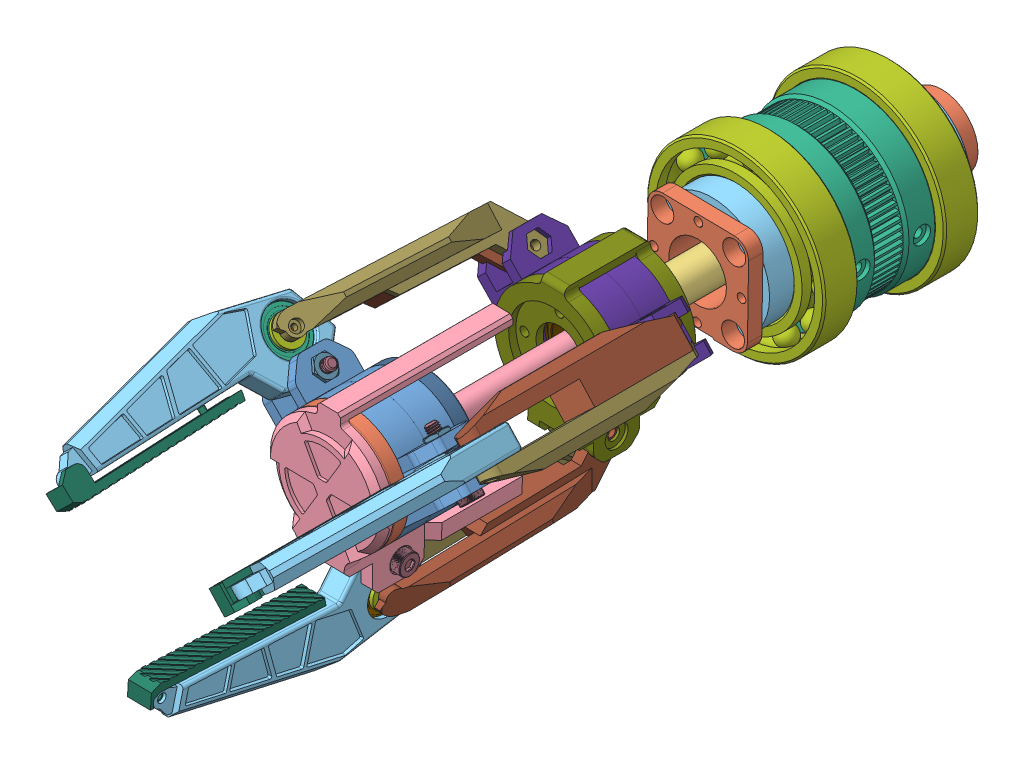
SolidWorks assembly CrawAssemV2, configuration EX2. Lengths in mm.
Overall size (95.83 96.83 278.95).
52 component instances, 26 part files, 110 mates.
Components (placement in the parent):
- CrawPivotL-1: CrawPivotL [Default] at (23.6534 28.2906 36.4169) x (0.675201 -0.737634 0) z (0 0 1)
- RotorInner-1: RotorInner [Default] at (23.6534 28.2906 51.4169) x (-0.675201 0.737634 0) z (0 0 -1)
- 4668K131_Permanently Lubricated Stainless Steel Ball Bearing-1: 4668K131_Permanently Lubricated Stainless Steel Ball Bearing [4668K131] at (23.6534 28.2906 52.4169) x (0.977927 0.208948 0) z (0 0 1)
- RotorOutter-1: RotorOutter [Default] at (23.6534 28.2906 56.4169) x (-0.999871 0.016078 0) z (0 0 -1)
- CrawPivotL-2: CrawPivotL [Default] at (23.6534 28.2906 36.4169) x (-0.716673 -0.697409 0) z (0 0 -1)
- FrontCraw-1: FrontCraw [Default] at (-7.9204 40.6623 113.525) x (-0.024761 0.025445 -0.99937) z (0.69697 -0.716221 -0.035504)
- FrontCraw-2: FrontCraw [Default] at (49.7643 43.7862 113.4714) x (0.035168 0.032192 -0.998863) z (-0.736795 -0.674433 -0.047677)
- 4668K334_Permanently Lubricated Stainless Steel Ball Bearing-1: 4668K334_Permanently Lubricated Stainless Steel Ball Bearing [4668K334] at (58.2277 46.2461 36.989) x (0.461728 0.422648 0.779857) z (-0.675201 0.737634 0)
- BearingStop1-1: BearingStop1 [Default] at (56.5397 48.0902 36.989) x (-0.727461 -0.665889 0.165503) z (0.675201 -0.737634 0)
- 4668K334_Permanently Lubricated Stainless Steel Ball Bearing-2: 4668K334_Permanently Lubricated Stainless Steel Ball Bearing [4668K334] at (-9.9873 48.3784 36.952) x (0.471273 -0.484291 0.737132) z (-0.716673 -0.697409 0)
- BearingStop1-2: BearingStop1 [Default] at (-11.779 46.6349 36.952) x (-0.683695 0.702579 -0.197341) z (0.716673 0.697409 0)
- BearingStop2-1: BearingStop2 [Default] at (55.6957 49.0123 36.989) x (-0.727461 -0.665889 0.165503) z (0.675201 -0.737634 0)
- BearingStop2-2: BearingStop2 [Default] at (-12.6749 45.7632 36.952) x (-0.683695 0.702579 -0.197341) z (0.716673 0.697409 0)
- FrontCraw-3: FrontCraw [Default] at (27.1452 -3.3521 113.4714) x (-0.000767 -0.047671 -0.998863) z (0.016059 0.998734 -0.047677)
- 7804K117_Stainless Steel Ball Bearing-1: 7804K117_Stainless Steel Ball Bearing [7804K117] at (23.1186 -11.1922 36.989) x (-0.007051 -0.438494 -0.898707) z (0.999871 -0.016078 0)
- BearingStop2-3: BearingStop2 [Default] at (19.3691 -11.1319 36.989) x (0.016038 0.997394 0.070343) z (0.999871 -0.016078 0)
- BearingStop1-3: BearingStop1 [Default] at (20.6189 -11.152 36.989) x (0.016038 0.997394 0.070343) z (0.999871 -0.016078 0)
- RotorInnerBack-1: RotorInnerBack [Default] at (23.6534 28.2906 21.4169) x (0.962311 -0.271952 0) z (0 0 1)
- SEC2pull1-1: SEC2pull1 [Default] at (-10.6231 40.787 37.118) x (0.023165 -0.023805 -0.999448) z (0.716673 0.697409 0)
- SEC2pull2-1: SEC2pull2 [Default] at (-3.4564 47.7611 37.118) x (0.023165 -0.023805 -0.999448) z (0.716673 0.697409 0)
- 91290A164_Black-Oxide Alloy Steel Socket Head Screw-1: 91290A164_Black-Oxide Alloy Steel Socket Head Screw [91290A164] at (23.2113 0.7942 36.4169) x (0.000258 0.016076 -0.999871) z (0.999871 -0.016078 0)
- 90592A090_Steel Hex Nut (1)-1: 90592A090_Steel Hex Nut (1) [90592A090] at (14.6124 0.9324 36.4169) x (0.016078 0.999871 0) z (0 0 1)
- 91290A164_Black-Oxide Alloy Steel Socket Head Screw-2: 91290A164_Black-Oxide Alloy Steel Socket Head Screw [91290A164] at (-0.6785 40.3897 36.4169) x (-0.0003 0.000308 -1) z (-0.716673 -0.697409 0)
- 90592A090_Steel Hex Nut (1)-2: 90592A090_Steel Hex Nut (1) [90592A090] at (4.0516 44.9926 36.4169) x (-0.348705 0.358336 -0.866025) z (-0.603974 0.620657 0.5)
- 91290A164_Black-Oxide Alloy Steel Socket Head Screw-3: 91290A164_Black-Oxide Alloy Steel Socket Head Screw [91290A164] at (48.6435 38.9643 36.4169) x (-0.209995 -0.192222 0.95862) z (0.675201 -0.737634 0)
- 90592A090_Steel Hex Nut (1)-3: 90592A090_Steel Hex Nut (1) [90592A090] at (44.1872 43.8327 36.4169) x (-0.368817 -0.3376 -0.866025) z (-0.63881 -0.584741 0.5)
- UpperSecCraw (1)-1: UpperSecCraw (1) [Default] at (-7.216 44.2401 113.6369) x (-0.024761 0.025445 -0.99937) z (0.716673 0.697409 0)
- UpperSecCraw (1)-2: UpperSecCraw (1) [Default] at (24.1122 -5.3749 113.6086) x (-0.000767 -0.047671 -0.998863) z (-0.999871 0.016078 0)
- UpperSecCraw (1)-3: UpperSecCraw (1) [Default] at (53.3178 42.9719 113.6086) x (0.035168 0.032192 -0.998863) z (0.675201 -0.737634 0)
- RTL-1: RTL [Default] at (23.6534 28.2906 -18.4955) x (-0.999871 0.016078 0) z (0 0 -1)
- PullPivot-1: PullPivot [Default] at (23.6534 28.2906 -38.4955) x (0.675201 -0.737634 0) z (0 0 1)
- 5972K213_Ball Bearing-1: 5972K213_Ball Bearing [5972K213] at (23.6534 28.2906 -33.4955)
- PullPivot2-1: PullPivot2 [Default] at (23.6534 28.2906 -38.4955) x (0.999025 -0.044147 0) z (0 0 1)
- PullPivot-2: PullPivot [Default] at (23.6534 28.2906 -38.4955) x (-0.716673 -0.697409 0) z (0 0 -1)
- 5972K213_Ball Bearing-2: 5972K213_Ball Bearing [5972K213] at (23.6534 28.2906 -43.4955) x (0.923728 0.383049 0) z (0 0 -1)
- PullPivot2-2: PullPivot2 [Default] at (23.6534 28.2906 -38.4955) x (-0.716673 -0.697409 0) z (0 0 -1)
- SEC2pull1-4: SEC2pull1 [Default] at (50.6589 47.1131 37.1398) x (-0.022244 -0.020361 -0.999545) z (0.675201 -0.737634 0)
- SEC2pull1-5: SEC2pull1 [Default] at (29.1982 -6.2916 37.1398) x (0.000485 0.030152 -0.999545) z (-0.999871 0.016078 0)
- SEC2pull2-7: SEC2pull2 [Default] at (19.5494 -6.1365 37.1398) x (0.000485 0.030152 -0.999545) z (-0.999871 0.016078 0)
- SEC2pull2-8: SEC2pull2 [Default] at (57.4109 39.7367 37.1398) x (-0.022244 -0.020361 -0.999545) z (0.675201 -0.737634 0)
- CylinderTube-1: CylinderTube [Default] at (23.6534 28.2906 -74.2503) x (-0.999871 0.016078 0) z (-0.016078 -0.999871 0)
- Hydro2-2: Hydro2 [Default] at (23.6534 28.2906 -50.4955) x (-0.999871 0.016078 0) z (0 0 -1) size (30 30 73)
- 6112K44_Linear Motion Shaft-1: 6112K44_Linear Motion Shaft [6112K44] at (23.6534 28.2906 -52.5831) x (-0.201275 -0.979535 0) z (0 0 1) size (8 8 100)
- Cylinder40mmCover-1: Cylinder40mmCover [Default] at (23.6534 28.2906 -79.2503) x (-0.999871 0.016078 0) z (0 0 -1) size (40 40 70)
- PiV1-1: PiV1 [Default] at (23.6534 28.2906 -129.2503) x (0.999871 -0.016078 0) z (0 0 1) size (55 55 30)
- PiVEnclosure1-1: PiVEnclosure1 [Default] at (23.6534 28.2906 -109.2503) x (0.791208 -0.611547 0) z (0 0 1) size (75 75 13) (hidden)
- 4668K334_Permanently Lubricated Stainless Steel Ball Bearing-3: 4668K334_Permanently Lubricated Stainless Steel Ball Bearing [4668K334] at (19.2674 62.5359 -106.7503) (hidden)
- 4668K334_Permanently Lubricated Stainless Steel Ball Bearing-4: 4668K334_Permanently Lubricated Stainless Steel Ball Bearing [4668K334] at (-10.5918 23.9046 -106.7503) (hidden)
- 4668K334_Permanently Lubricated Stainless Steel Ball Bearing-5: 4668K334_Permanently Lubricated Stainless Steel Ball Bearing [4668K334] at (28.0395 -5.9546 -106.7503) (hidden)
- 4668K334_Permanently Lubricated Stainless Steel Ball Bearing-6: 4668K334_Permanently Lubricated Stainless Steel Ball Bearing [4668K334] at (57.8987 32.6767 -106.7503) (hidden)
- 5972K249_Ball Bearing-1: 5972K249_Ball Bearing [5972K249] at (23.6534 28.2906 -93.2503) x (0.88466 0.466238 0) z (0 0 1) size (62 62 12)
- 5972K249_Ball Bearing-2: 5972K249_Ball Bearing [5972K249] at (23.6534 28.2906 -135.2503) x (0.910111 -0.414364 0) z (0 0 1) size (62 62 12)
Mates (geometry in assembly coordinates):
- Concentric1: concentric aligned: cylinder of CrawPivotL-1 through (36.9309 40.4442 36.4169) axis (0 0 1) radius 1.3; cylinder of RotorInner-1 through (36.9309 40.4442 43.4169) axis (0 0 1) radius 1.15
- Concentric2: concentric aligned: circle of CrawPivotL-1; cylinder of RotorInner-1 through (40.8175 22.8689 43.4169) axis (0 0 1) radius 1.15
- Coincident2: coincident anti-aligned: plane of CrawPivotL-1 through (23.6534 28.2906 46.4169) normal (0 0 1); plane of RotorInner-1 through (23.6534 28.2906 46.4169) normal (0 0 -1)
- Concentric3: concentric anti-aligned: cylinder of RotorInner-1 through (23.6534 28.2906 54.9169) axis (0 0 -1) radius 3.85; cylinder of 4668K131_Permanently Lubricated Stainless Steel Ball Bearing-1 through (23.6534 28.2906 54.4169) axis (0 0 1) radius 4
- Coincident3: coincident anti-aligned: plane of RotorInner-1 through (23.6534 28.2906 50.4169) normal (0 0 1); plane of 4668K131_Permanently Lubricated Stainless Steel Ball Bearing-1 through (22.4926 33.7235 50.4169) normal (0 0 -1)
- Concentric4: concentric anti-aligned: cylinder of 4668K131_Permanently Lubricated Stainless Steel Ball Bearing-1 through (23.6534 28.2906 54.4169) axis (0 0 1) radius 8; cylinder of RotorOutter-1 through (23.6534 28.2906 54.4169) axis (0 0 -1) radius 8
- Coincident4: coincident anti-aligned: plane of 4668K131_Permanently Lubricated Stainless Steel Ball Bearing-1 through (22.0237 35.9184 54.4169) normal (0 0 1); plane of RotorOutter-1 through (23.6534 28.2906 54.4169) normal (0 0 -1)
- Coincident5: coincident anti-aligned: plane of CrawPivotL-1 through (23.6534 28.2906 36.4169) normal (0 0 -1); plane of CrawPivotL-2 through (23.6534 28.2906 36.4169) normal (0 0 1)
- Coincident6: coincident anti-aligned: circle of CrawPivotL-1; circle of CrawPivotL-2
- Concentric7: concentric anti-aligned: cylinder of FrontCraw-2 through (56.5397 48.0902 36.989) axis (0.675201 -0.737634 0) radius 8; cylinder of 4668K334_Permanently Lubricated Stainless Steel Ball Bearing-1 through (56.5397 48.0902 36.989) axis (-0.675201 0.737634 0) radius 8
- Coincident10: coincident anti-aligned: plane of FrontCraw-2 through (56.5397 48.0902 36.989) normal (0.675201 -0.737634 0); plane of 4668K334_Permanently Lubricated Stainless Steel Ball Bearing-1 through (60.9979 52.1711 32.1378) normal (-0.675201 0.737634 0)
- Concentric8: concentric aligned: cylinder of 4668K334_Permanently Lubricated Stainless Steel Ball Bearing-1 through (56.5397 48.0902 36.989) axis (-0.675201 0.737634 0) radius 4; cylinder of BearingStop1-1 through (59.9157 44.4021 36.989) axis (-0.675201 0.737634 0) radius 3.9
- Coincident11: coincident anti-aligned: plane of 4668K334_Permanently Lubricated Stainless Steel Ball Bearing-1 through (63.0477 47.2689 33.581) normal (0.675201 -0.737634 0); plane of BearingStop1-1 through (59.9157 44.4021 36.989) normal (-0.675201 0.737634 0)
- Concentric9: concentric anti-aligned: cylinder of FrontCraw-1 through (-11.779 46.6349 36.952) axis (0.716673 0.697409 0) radius 8; cylinder of 4668K334_Permanently Lubricated Stainless Steel Ball Bearing-2 through (-11.779 46.6349 36.952) axis (-0.716673 -0.697409 0) radius 8
- Coincident12: coincident anti-aligned: plane of FrontCraw-1 through (-11.779 46.6349 36.952) normal (0.716673 0.697409 0); plane of 4668K334_Permanently Lubricated Stainless Steel Ball Bearing-2 through (-15.7632 50.7291 42.189) normal (-0.716673 -0.697409 0)
- Concentric11: concentric aligned: cylinder of 4668K334_Permanently Lubricated Stainless Steel Ball Bearing-2 through (-11.779 46.6349 36.952) axis (-0.716673 -0.697409 0) radius 4; cylinder of BearingStop1-2 through (-8.1957 50.122 36.952) axis (-0.716673 -0.697409 0) radius 3.9
- Coincident13: coincident anti-aligned: plane of 4668K334_Permanently Lubricated Stainless Steel Ball Bearing-2 through (-10.9946 52.9982 40.631) normal (0.716673 0.697409 0); plane of BearingStop1-2 through (-8.1957 50.122 36.952) normal (-0.716673 -0.697409 0)
- Concentric12: concentric aligned: cylinder of BearingStop1-1 through (60.7598 43.48 36.989) axis (-0.675201 0.737634 0) radius 3.05; cylinder of BearingStop2-1 through (60.591 43.6644 36.989) axis (-0.675201 0.737634 0) radius 2.95
- Coincident15: coincident anti-aligned: circle of BearingStop1-1; plane of BearingStop2-1 through (56.5397 48.0902 36.989) normal (0.675201 -0.737634 0)
- Concentric13: concentric aligned: cylinder of BearingStop1-2 through (-7.2998 50.9937 36.952) axis (-0.716673 -0.697409 0) radius 3.05; cylinder of BearingStop2-2 through (-7.479 50.8194 36.952) axis (-0.716673 -0.697409 0) radius 2.95
- Coincident17: coincident anti-aligned: plane of BearingStop1-2 through (-11.779 46.6349 36.952) normal (-0.716673 -0.697409 0); plane of BearingStop2-2 through (-11.779 46.6349 36.952) normal (0.716673 0.697409 0)
- Concentric14: concentric aligned: circle of RotorOutter-1; circle of FrontCraw-3
- Coincident18: coincident anti-aligned: plane of RotorOutter-1 through (27.1465 -3.2696 56.4169) normal (-0.999871 0.016078 0); plane of FrontCraw-3 through (27.1452 -3.3521 113.4714) normal (0.999871 -0.016078 0)
- Concentric15: concentric anti-aligned: cylinder of FrontCraw-3 through (25.6183 -11.2324 36.989) axis (-0.999871 0.016078 0) radius 8; cylinder of 7804K117_Stainless Steel Ball Bearing-1 through (25.6183 -11.2324 36.989) axis (0.999871 -0.016078 0) radius 8
- Coincident20: coincident anti-aligned: plane of FrontCraw-3 through (25.6183 -11.2324 36.989) normal (-0.999871 0.016078 0); plane of 7804K117_Stainless Steel Ball Bearing-1 through (25.698 -6.2754 34.5697) normal (0.999871 -0.016078 0)
- Concentric16: concentric anti-aligned: cylinder of 7804K117_Stainless Steel Ball Bearing-1 through (25.6183 -11.2324 36.989) axis (0.999871 -0.016078 0) radius 4; cylinder of BearingStop1-3 through (25.6183 -11.2324 36.989) axis (-0.999871 0.016078 0) radius 3.9
- Coincident21: coincident anti-aligned: plane of 7804K117_Stainless Steel Ball Bearing-1 through (25.698 -6.2754 34.5697) normal (0.999871 -0.016078 0); plane of BearingStop1-3 through (25.6183 -11.2324 36.989) normal (-0.999871 0.016078 0)
- Concentric17: concentric aligned: cylinder of BearingStop2-3 through (26.6181 -11.2485 36.989) axis (-0.999871 0.016078 0) radius 2.95; cylinder of BearingStop1-3 through (26.8681 -11.2525 36.989) axis (-0.999871 0.016078 0) radius 3.05
- Coincident23: coincident anti-aligned: plane of 7804K117_Stainless Steel Ball Bearing-1 through (20.6803 -7.333 35.1252) normal (-0.999871 0.016078 0); plane of BearingStop2-3 through (20.6189 -11.152 36.989) normal (0.999871 -0.016078 0)
- Concentric18: concentric aligned: cylinder of CrawPivotL-2 through (28.5486 45.6122 36.4169) axis (0 0 -1) radius 1.3; cylinder of RotorInnerBack-1 through (28.5486 45.6122 29.4169) axis (0 0 -1) radius 0.725
- Concentric19: concentric aligned: cylinder of CrawPivotL-2 through (11.1001 41.1907 36.4169) axis (0 0 -1) radius 1.3; cylinder of RotorInnerBack-1 through (11.1001 41.1907 29.4169) axis (0 0 -1) radius 0.725
- Coincident24: coincident anti-aligned: plane of CrawPivotL-2 through (23.6534 28.2906 26.4169) normal (0 0 -1); plane of RotorInnerBack-1 through (23.6534 28.2906 26.4169) normal (0 0 1)
- Concentric26: concentric aligned: cylinder of BearingStop2-2 through (-7.479 50.8194 36.952) axis (-0.716673 -0.697409 0) radius 2.05; cylinder of SEC2pull1-1 through (-6.9415 51.3424 36.952) axis (-0.716673 -0.697409 0) radius 1.8
- Coincident28: coincident anti-aligned: plane of BearingStop2-2 through (-12.6749 45.7632 36.952) normal (-0.716673 -0.697409 0); plane of SEC2pull1-1 through (-12.6749 45.7632 36.952) normal (0.716673 0.697409 0)
- Coincident32: coincident anti-aligned: circle of SEC2pull1-1; circle of SEC2pull2-1
- Concentric29: concentric aligned: circle of SEC2pull1-1; cylinder of SEC2pull2-1 through (-8.0165 50.2963 36.952) axis (0.716673 0.697409 0) radius 1
- Concentric35: concentric anti-aligned: circle of RotorOutter-1; circle of 91290A164_Black-Oxide Alloy Steel Socket Head Screw-1
- Coincident38: coincident anti-aligned: plane of RotorOutter-1 through (30.2104 0.6816 36.4169) normal (0.999871 -0.016078 0); plane of 91290A164_Black-Oxide Alloy Steel Socket Head Screw-1 through (30.2096 0.6286 39.7164) normal (-0.999871 0.016078 0)
- Concentric36: concentric anti-aligned: circle of RotorOutter-1; circle of 90592A090_Steel Hex Nut (1)-1
- Coincident39: coincident anti-aligned: plane of RotorOutter-1 through (16.6544 28.4032 56.4169) normal (-0.999871 0.016078 0); plane of 90592A090_Steel Hex Nut (1)-1 through (16.1559 -2.5928 34.3961) normal (0.999871 -0.016078 0)
- Coincident40: coincident aligned: circle of CrawPivotL-2; circle of 91290A164_Black-Oxide Alloy Steel Socket Head Screw-2
- Coincident41: coincident aligned: circle of CrawPivotL-2; circle of 90592A090_Steel Hex Nut (1)-2
- Coincident42: coincident anti-aligned: plane of CrawPivotL-2 through (0.464 46.3851 34.3961) normal (0.697409 -0.716673 0); plane of 90592A090_Steel Hex Nut (1)-2 through (0.464 46.3851 38.4376) normal (-0.697409 0.716673 0)
- Coincident43: coincident anti-aligned: plane of RotorOutter-1 through (16.2685 4.4063 38.4376) normal (-0.016078 -0.999871 0); plane of 90592A090_Steel Hex Nut (1)-1 through (13.0689 4.4577 38.4376) normal (0.016078 0.999871 0)
- Coincident44: coincident anti-aligned: plane of CrawPivotL-2 through (-14.723 47.6528 46.4169) normal (0.716673 0.697409 0); plane of FrontCraw-1 through (-7.9204 40.6623 113.525) normal (-0.716673 -0.697409 0)
- Coincident45: coincident aligned: circle of CrawPivotL-1; circle of 91290A164_Black-Oxide Alloy Steel Socket Head Screw-3
- Coincident46: coincident aligned: circle of CrawPivotL-1; circle of 90592A090_Steel Hex Nut (1)-3
- Coincident47: coincident anti-aligned: plane of CrawPivotL-1 through (47.8492 45.0157 38.4376) normal (-0.737634 -0.675201 0); plane of 90592A090_Steel Hex Nut (1)-3 through (47.8492 45.0157 34.3961) normal (0.737634 0.675201 0)
- Concentric39: concentric anti-aligned: cylinder of FrontCraw-1 through (-9.366 42.1478 113.6369) axis (0.716673 0.697409 0) radius 2; cylinder of UpperSecCraw (1)-1 through (-5.066 46.3323 113.6369) axis (-0.716673 -0.697409 0) radius 1.975
- Coincident49: coincident anti-aligned: plane of FrontCraw-1 through (-9.8607 51.2595 115.1168) normal (0.716673 0.697409 0); plane of UpperSecCraw (1)-1 through (-5.066 46.3323 113.6369) normal (-0.716673 -0.697409 0)
- Parallel1: parallel anti-aligned: plane of FrontCraw-1 through (-2.1871 46.2416 113.525) normal (0.69697 -0.716221 -0.035504); plane of UpperSecCraw (1)-1 through (-5.987 44.411 68.9439) normal (-0.69697 0.716221 0.035504)
- Concentric40: concentric anti-aligned: cylinder of FrontCraw-3 through (27.1119 -5.4231 113.6086) axis (-0.999871 0.016078 0) radius 2; cylinder of UpperSecCraw (1)-2 through (21.1126 -5.3267 113.6086) axis (0.999871 -0.016078 0) radius 1.975
- Coincident52: coincident anti-aligned: plane of FrontCraw-3 through (21.0024 -12.1823 115.1721) normal (-0.999871 0.016078 0); plane of UpperSecCraw (1)-2 through (21.1126 -5.3267 113.6086) normal (0.999871 -0.016078 0)
- Parallel3: parallel anti-aligned: plane of FrontCraw-3 through (19.1462 -3.2235 113.4714) normal (0.016059 0.998734 -0.047677); plane of UpperSecCraw (1)-2 through (23.1154 -5.1688 68.91) normal (-0.016059 -0.998734 0.047677)
- Concentric41: concentric anti-aligned: cylinder of FrontCraw-2 through (51.2922 45.1848 113.6086) axis (0.675201 -0.737634 0) radius 2; cylinder of UpperSecCraw (1)-3 through (55.3434 40.759 113.6086) axis (-0.675201 0.737634 0) radius 1.975
- Coincident54: coincident anti-aligned: plane of FrontCraw-2 through (60.401 45.3885 115.1721) normal (0.675201 -0.737634 0); plane of UpperSecCraw (1)-3 through (55.3434 40.759 113.6086) normal (-0.675201 0.737634 0)
- Parallel4: parallel anti-aligned: plane of FrontCraw-2 through (55.1659 37.8852 113.4714) normal (-0.736795 -0.674433 -0.047677); plane of UpperSecCraw (1)-3 through (53.8528 42.1059 68.91) normal (0.736795 0.674433 0.047677)
- Coincident59: coincident anti-aligned: circle of RTL-1; circle of PullPivot-1
- Concentric49: concentric aligned: cylinder of PullPivot-1 through (23.6534 28.2906 -38.4955) axis (0 0 1) radius 12; cylinder of 5972K213_Ball Bearing-1 through (23.6534 28.2906 -30.9955) axis (0 0 1) radius 12
- Coincident61: coincident anti-aligned: plane of PullPivot-1 through (23.6534 28.2906 -30.9955) normal (0 0 -1); plane of 5972K213_Ball Bearing-1 through (23.6534 40.0406 -30.9955) normal (0 0 1)
- Coincident62: coincident anti-aligned: circle of PullPivot-1; circle of PullPivot2-1
- Concentric50: concentric aligned: cylinder of PullPivot-1 through (12.5889 18.1626 -28.4955) axis (0 0 -1) radius 2; cylinder of PullPivot2-1 through (12.5889 18.1626 -35.9955) axis (0 0 -1) radius 2
- Concentric52: concentric anti-aligned: circle of RotorInnerBack-1; circle of RTL-1
- Concentric53: concentric aligned: cylinder of PullPivot-2 through (23.6534 28.2906 -38.4955) axis (0 0 -1) radius 12; cylinder of 5972K213_Ball Bearing-2 through (23.6534 28.2906 -45.9955) axis (0 0 -1) radius 12
- Coincident65: coincident anti-aligned: plane of PullPivot-2 through (23.6534 28.2906 -45.9955) normal (0 0 1); plane of 5972K213_Ball Bearing-2 through (28.1543 17.4368 -45.9955) normal (0 0 -1)
- Coincident66: coincident anti-aligned: circle of PullPivot-2; circle of PullPivot2-2
- Concentric54: concentric aligned: cylinder of PullPivot-2 through (23.8578 43.2892 -48.4955) axis (0 0 1) radius 2; cylinder of PullPivot2-2 through (23.8578 43.2892 -40.9955) axis (0 0 1) radius 2
- Coincident67: coincident aligned: circle of RTL-1; circle of PullPivot-2
- Concentric56: concentric aligned: cylinder of BearingStop2-1 through (60.591 43.6644 36.989) axis (-0.675201 0.737634 0) radius 2.05; cylinder of SEC2pull1-4 through (61.0974 43.1112 36.989) axis (-0.675201 0.737634 0) radius 1.8
- Coincident68: coincident anti-aligned: plane of BearingStop2-1 through (55.6957 49.0123 36.989) normal (-0.675201 0.737634 0); plane of SEC2pull1-4 through (55.6957 49.0123 36.989) normal (0.675201 -0.737634 0)
- Coincident72: coincident anti-aligned: plane of SEC2pull1-4 through (61.0974 43.1112 36.989) normal (0.675201 -0.737634 0); plane of SEC2pull2-8 through (61.0974 43.1112 36.989) normal (-0.675201 0.737634 0)
- Concentric63: concentric anti-aligned: cylinder of SEC2pull1-4 through (44.491 43.5008 -38.4955) axis (0.675201 -0.737634 0) radius 1.5; cylinder of SEC2pull2-8 through (53.6062 33.5427 -38.4955) axis (-0.675201 0.737634 0) radius 1.5
- Concentric65: concentric anti-aligned: cylinder of BearingStop2-3 through (26.6181 -11.2485 36.989) axis (-0.999871 0.016078 0) radius 2.05; cylinder of SEC2pull1-5 through (19.1191 -11.1279 36.989) axis (0.999871 -0.016078 0) radius 1.8
- Coincident73: coincident anti-aligned: plane of BearingStop2-3 through (26.6181 -11.2485 36.989) normal (0.999871 -0.016078 0); plane of SEC2pull1-5 through (26.6181 -11.2485 36.989) normal (-0.999871 0.016078 0)
- Concentric66: concentric anti-aligned: cylinder of SEC2pull1-5 through (29.1178 -11.2887 36.989) axis (-0.999871 0.016078 0) radius 0.5; circle of SEC2pull2-7
- Coincident74: coincident anti-aligned: plane of BearingStop2-3 through (19.969 -11.1416 36.989) normal (-0.999871 0.016078 0); plane of SEC2pull2-7 through (19.969 -11.1416 36.989) normal (0.999871 -0.016078 0)
- Concentric67: concentric anti-aligned: cylinder of SEC2pull1-5 through (30.8103 0.672 -38.4955) axis (-0.999871 0.016078 0) radius 1.5; cylinder of SEC2pull2-7 through (17.662 0.8834 -38.4955) axis (0.999871 -0.016078 0) radius 1.5
- Concentric73: concentric anti-aligned: cylinder of PullPivot-1 through (29.0627 60.3557 -38.4955) axis (0.675201 -0.737634 0) radius 2; cylinder of SEC2pull2-8 through (53.6062 33.5427 -38.4955) axis (-0.675201 0.737634 0) radius 1.5
- Concentric77: concentric aligned: cylinder of RTL-1 through (43.2087 0.4726 -38.4955) axis (-0.999871 0.016078 0) radius 2.05; cylinder of SEC2pull1-5 through (30.8103 0.672 -38.4955) axis (-0.999871 0.016078 0) radius 1.5
- Tangent1: tangent aligned: cylinder of FrontCraw-1 through (-4.4187 37.0639 36.5259) axis (0.716673 0.697409 0) radius 2.25; cylinder of 91290A164_Black-Oxide Alloy Steel Socket Head Screw-2 through (7.2049 48.0612 36.4169) axis (0.716673 0.697409 0) radius 2
- Concentric80: concentric anti-aligned: cylinder of FrontCraw-2 through (46.7529 41.0297 36.4169) axis (0.675201 -0.737634 0) radius 2.25; cylinder of 91290A164_Black-Oxide Alloy Steel Socket Head Screw-3 through (41.2163 47.0783 36.4169) axis (-0.675201 0.737634 0) radius 2
- Parallel9: parallel aligned: plane of RotorOutter-1 through (20.0333 51.9478 -5.5831) normal (0.016078 0.999871 0); plane of CylinderTube-1 through (41.4325 45.507 -79.2503) normal (0.016078 0.999871 0)
- Concentric89: concentric aligned: cylinder of SEC2pull1-4 through (54.3453 50.4875 36.989) axis (0.675201 -0.737634 0) radius 0.5; cylinder of SEC2pull2-8 through (60.0846 44.2176 36.989) axis (0.675201 -0.737634 0) radius 1
- Concentric90: concentric anti-aligned: cylinder of RTL-1 through (23.6534 28.2906 -18.4955) axis (0 0 -1) radius 15; cylinder of Hydro2-2 through (23.6534 28.2906 -53.4955) axis (0 0 1) radius 15
- Concentric91: concentric aligned: cylinder of RTL-1 through (23.8383 39.7891 -48.4955) axis (0 0 -1) radius 2; cylinder of Hydro2-2 through (23.8383 39.7891 -50.4955) axis (0 0 -1) radius 2
- Coincident85: coincident anti-aligned: plane of RTL-1 through (23.6534 28.2906 -50.4955) normal (0 0 -1); plane of Hydro2-2 through (23.6534 28.2906 -50.4955) normal (0 0 1)
- Concentric92: concentric anti-aligned: cylinder of Hydro2-2 through (23.6534 28.2906 -110.4955) axis (0 0 1) radius 4.1; cylinder of 6112K44_Linear Motion Shaft-1 through (23.6534 28.2906 47.4169) axis (0 0 -1) radius 4
- Coincident86: coincident anti-aligned: plane of RotorInner-1 through (23.6534 28.2906 47.4169) normal (0 0 -1); plane of 6112K44_Linear Motion Shaft-1 through (23.6534 28.2906 47.4169) normal (0 0 1)
- Concentric94: concentric aligned: cylinder of CylinderTube-1 through (23.6534 28.2906 -159.2503) axis (0 0 1) radius 12.5; cylinder of Hydro2-2 through (23.6534 28.2906 -123.4955) axis (0 0 1) radius 8.5
- Concentric95: concentric aligned: cylinder of CylinderTube-1 through (23.6534 28.2906 -159.2503) axis (0 0 1) radius 12.5; cylinder of Cylinder40mmCover-1 through (23.6534 28.2906 -149.2503) axis (0 0 1) radius 12.6
- Concentric96: concentric aligned: cylinder of CylinderTube-1 through (23.8986 43.5386 -159.2503) axis (0 0 1) radius 1.5; cylinder of Cylinder40mmCover-1 through (23.8986 43.5386 -89.2503) axis (0 0 1) radius 1.5
- Coincident87: coincident anti-aligned: plane of CylinderTube-1 through (23.6534 28.2906 -79.2503) normal (0 0 -1); plane of Cylinder40mmCover-1 through (23.6534 28.2906 -79.2503) normal (0 0 1)
- Concentric97: concentric aligned: cylinder of Cylinder40mmCover-1 through (23.6534 28.2906 -149.2503) axis (0 0 1) radius 20; cylinder of PiV1-1 through (23.6534 28.2906 -129.2503) axis (0 0 1) radius 20.5
- Concentric98: concentric anti-aligned: cylinder of Cylinder40mmCover-1 through (43.6509 27.9691 -124.7503) axis (-0.999871 0.016078 0) radius 1.55; cylinder of PiV1-1 through (-3.843 28.7328 -124.7503) axis (0.999871 -0.016078 0) radius 1.55
- Concentric99: concentric aligned: cylinder of Cylinder40mmCover-1 through (23.6534 28.2906 -149.2503) axis (0 0 1) radius 20; cylinder of PiVEnclosure1-1 through (23.6534 28.2906 -99.2503) axis (0 0 1) radius 22.5
- Coincident89: coincident anti-aligned: plane of PiV1-1 through (23.6534 28.2906 -99.2503) normal (0 0 1); plane of PiVEnclosure1-1 through (23.6534 28.2906 -99.2503) normal (0 0 -1)
- Concentric100: concentric aligned: cylinder of PiVEnclosure1-1 through (57.8987 32.6767 -109.2503) axis (0 0 1) radius 3.9; cylinder of 4668K334_Permanently Lubricated Stainless Steel Ball Bearing-6 through (57.8987 32.6767 -104.2503) axis (0 0 1) radius 4
- Concentric101: concentric aligned: cylinder of PiVEnclosure1-1 through (19.2674 62.5359 -109.2503) axis (0 0 1) radius 3.9; cylinder of 4668K334_Permanently Lubricated Stainless Steel Ball Bearing-3 through (19.2674 62.5359 -104.2503) axis (0 0 1) radius 4
- Concentric102: concentric aligned: cylinder of PiVEnclosure1-1 through (28.0395 -5.9546 -109.2503) axis (0 0 1) radius 3.9; cylinder of 4668K334_Permanently Lubricated Stainless Steel Ball Bearing-5 through (28.0395 -5.9546 -104.2503) axis (0 0 1) radius 4
- Concentric103: concentric aligned: cylinder of PiVEnclosure1-1 through (-10.5918 23.9046 -109.2503) axis (0 0 1) radius 3.9; cylinder of 4668K334_Permanently Lubricated Stainless Steel Ball Bearing-4 through (-10.5918 23.9046 -104.2503) axis (0 0 1) radius 4
- Coincident90: coincident anti-aligned: plane of PiVEnclosure1-1 through (6.5308 26.0976 -104.2503) normal (0 0 -1); plane of 4668K334_Permanently Lubricated Stainless Steel Ball Bearing-4 through (-10.5918 29.349 -104.2503) normal (0 0 1)
- Coincident91: coincident anti-aligned: plane of PiVEnclosure1-1 through (21.4604 45.4133 -104.2503) normal (0 0 -1); plane of 4668K334_Permanently Lubricated Stainless Steel Ball Bearing-3 through (19.2674 67.9803 -104.2503) normal (0 0 1)
- Coincident92: coincident anti-aligned: plane of PiVEnclosure1-1 through (25.8465 11.168 -104.2503) normal (0 0 -1); plane of 4668K334_Permanently Lubricated Stainless Steel Ball Bearing-5 through (28.0395 -0.5102 -104.2503) normal (0 0 1)
- Coincident93: coincident anti-aligned: circle of PiVEnclosure1-1; plane of 4668K334_Permanently Lubricated Stainless Steel Ball Bearing-6 through (57.8987 38.1211 -104.2503) normal (0 0 1)
- Concentric105: concentric aligned: cylinder of Cylinder40mmCover-1 through (23.6534 28.2906 -149.2503) axis (0 0 1) radius 20; cylinder of 5972K249_Ball Bearing-1 through (23.6534 28.2906 -87.2503) axis (0 0 1) radius 19.9995
- Coincident94: coincident anti-aligned: plane of PiV1-1 through (23.6534 28.2906 -99.2503) normal (0 0 1); plane of 5972K249_Ball Bearing-1 through (14.0492 46.5142 -99.2503) normal (0 0 -1)
- Concentric106: concentric aligned: cylinder of Cylinder40mmCover-1 through (23.6534 28.2906 -149.2503) axis (0 0 1) radius 20; cylinder of 5972K249_Ball Bearing-2 through (23.6534 28.2906 -129.2503) axis (0 0 1) radius 19.9995
- Coincident95: coincident anti-aligned: plane of PiV1-1 through (23.6534 28.2906 -129.2503) normal (0 0 -1); plane of 5972K249_Ball Bearing-2 through (33.3089 49.498 -129.2503) normal (0 0 1)
- Coincident96: coincident anti-aligned: plane of CrawPivotL-1 through (33.2413 17.8162 36.4169) normal (-0.675201 0.737634 0); plane of FrontCraw-2 through (55.1659 37.8852 113.4714) normal (0.675201 -0.737634 0)
- Concentric107: concentric anti-aligned: cylinder of SEC2pull1-1 through (-6.6627 34.5663 -38.4955) axis (0.716673 0.697409 0) radius 1.5; cylinder of SEC2pull2-1 through (3.0124 43.9814 -38.4955) axis (-0.716673 -0.697409 0) radius 1.5
